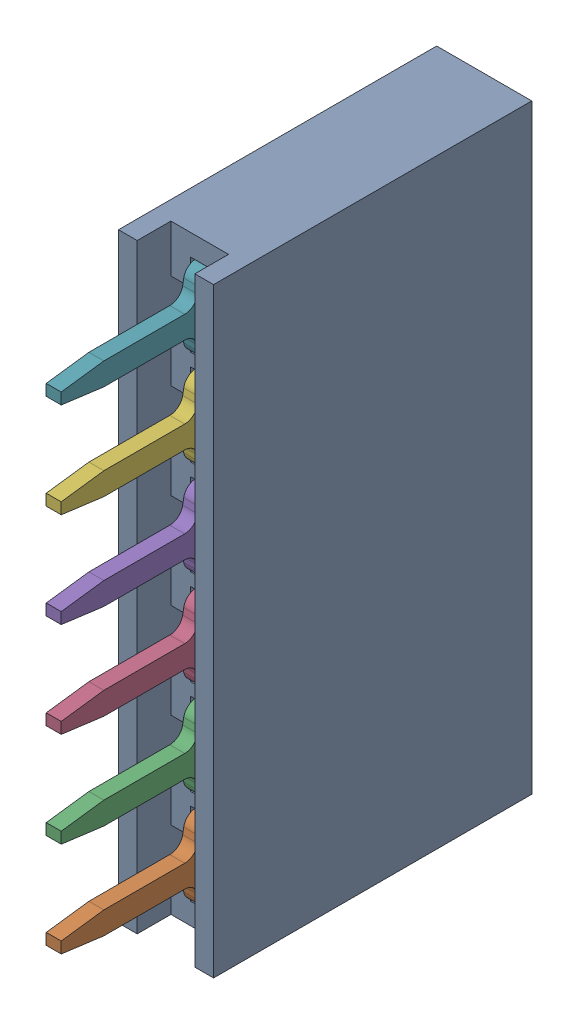
SolidWorks assembly H1_1.step, configuration Default. Lengths in mm.
Overall size (2.54 16.04 11.5).
8 component instances, 2 part files, 0 mates.
Components (placement in the parent):
- DS1023-1x6SF11_1.step-3: DS1023-1x6SF11_1.step [Default] at (486.5324 321.8178 -1.647) x (0 1 0) z (0 0 -1) size (16.04 2.54 11.5)
  - body_3.step-8: body_3.step [Default] at origin size (16.04 2.54 8.5)
  - contact_1.step-51: contact_1.step [Default] at origin size (2.3 0.4 9)
  - contact_1.step-52: contact_1.step [Default] at (2.54 0 0) size (2.3 0.4 9)
  - contact_1.step-55: contact_1.step [Default] at (5.08 0 0) size (2.3 0.4 9)
  - contact_1.step-56: contact_1.step [Default] at (7.62 0 0) size (2.3 0.4 9)
  - contact_1.step-57: contact_1.step [Default] at (10.16 0 0) size (2.3 0.4 9)
  - contact_1.step-58: contact_1.step [Default] at (12.7 0 0) size (2.3 0.4 9)
